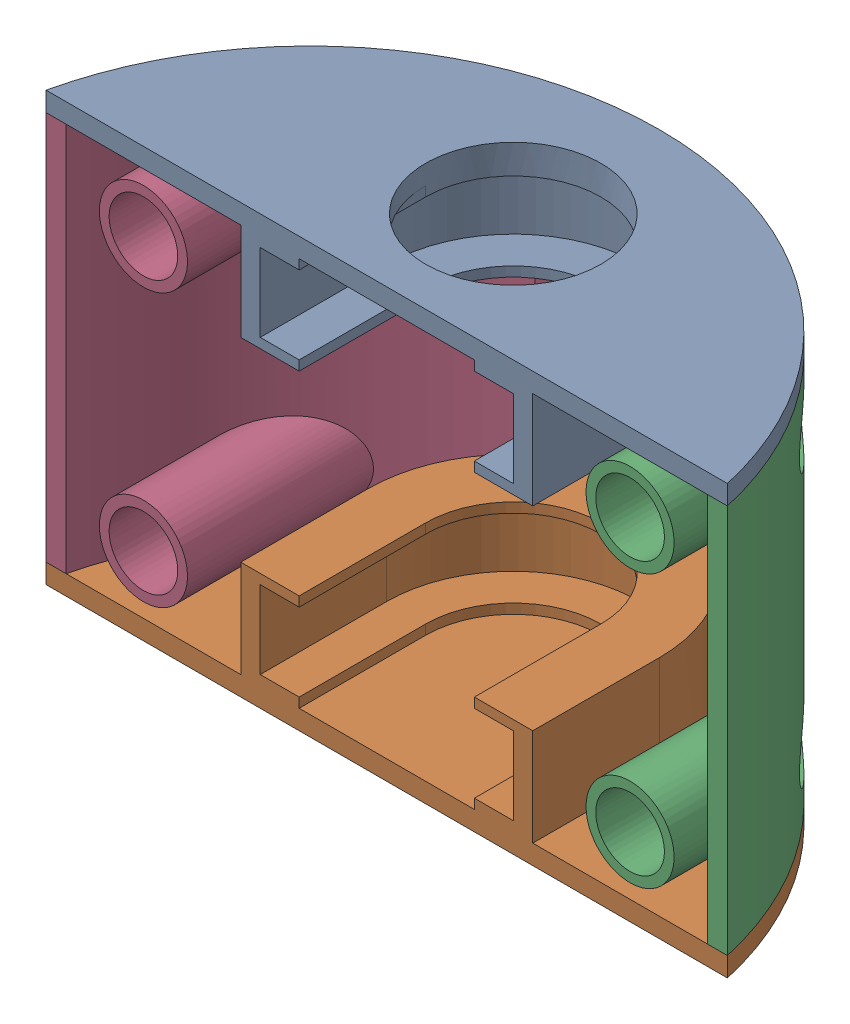
SolidWorks assembly side_wheel_cover, configuration Default. Lengths in mm.
Overall size (70 44 28).
3 component instances, 3 part files, 6 mates.
Components (placement in the parent):
- side_wheel_cover_down-1: side_wheel_cover_down [Default] at (3.0681 6.4262 -4.4939) size (70 12 28)
- side_wheel_cover_up-1: side_wheel_cover_up [Default] at (3.0681 -33.5738 -4.4939) x (-1 0 0) z (0 0 1) size (70 12 28)
- side_wheel_cover_boundary-1: side_wheel_cover_boundary [Default] at (3.0681 6.4262 -4.4939) x (-1 0 0) z (0 0 1) size (70 40 28)
Mates (geometry in assembly coordinates):
- Concentric1: concentric aligned: cylinder of side_wheel_cover_up-1 through (3.0681 -35.5738 16.3811) axis (0 1 0) radius 35.875; cylinder of side_wheel_cover_boundary-1 through (3.0681 -33.5738 16.3811) axis (0 1 0) radius 35.875
- Concentric2: concentric anti-aligned: circle of side_wheel_cover_down-1; cylinder of side_wheel_cover_boundary-1 through (3.0681 -33.5738 16.3811) axis (0 1 0) radius 35.875
- Parallel1: parallel aligned: plane of side_wheel_cover_down-1 through (3.0681 8.4262 8.5061) normal (0 0 1); plane of side_wheel_cover_up-1 through (3.0681 -35.5738 8.5061) normal (0 0 1)
- Parallel2: parallel aligned: plane of side_wheel_cover_down-1 through (3.0681 8.4262 8.5061) normal (0 0 1); plane of side_wheel_cover_boundary-1 through (3.0681 -33.5738 8.5061) normal (0 0 1)
- Coincident1: coincident anti-aligned: plane of side_wheel_cover_down-1 through (3.0681 6.4262 -4.4939) normal (0 -1 0); plane of side_wheel_cover_boundary-1 through (3.0681 6.4262 -4.4939) normal (0 1 0)
- Coincident2: coincident anti-aligned: plane of side_wheel_cover_up-1 through (3.0681 -33.5738 -4.4939) normal (0 1 0); plane of side_wheel_cover_boundary-1 through (3.0681 -33.5738 -4.4939) normal (0 -1 0)
